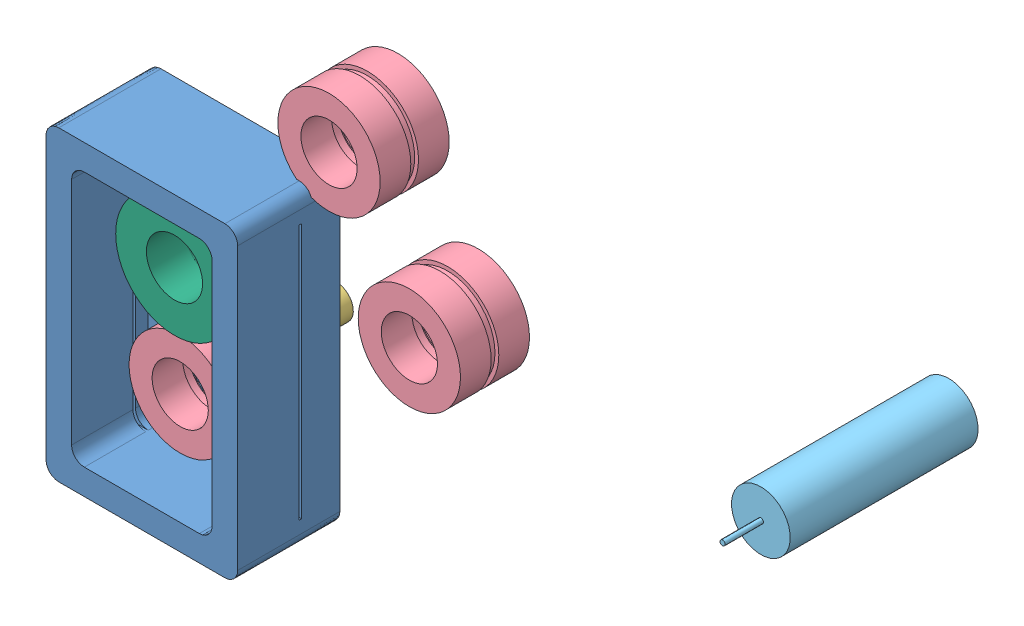
SolidWorks assembly MotorHolderAssembly, configuration Default. Lengths in mm.
Overall size (54.59 39.49 38.35).
8 component instances, 6 part files, 7 mates.
Components (placement in the parent):
- Holder-1: Holder [Default] at (-12.0978 19.1611 -15.3648) size (19.05 30.48 10.16)
- BallbearingPinchRollInterface-1: BallbearingPinchRollInterface [Default] at (-10.3379 24.5042 -15.3648) x (-0.976423 -0.215867 0) z (0 0 -1) size (3.3 3.3 8.38)
- MotorPinchRollInterface-1: MotorPinchRollInterface [Default] at (-9.8767 12.9721 -15.3648) x (-0.80394 -0.59471 0) z (0 0 -1) size (3.3 3.3 9.53)
- WheelTreads5-1: WheelTreads5 [Default] at (-9.5578 13.0937 -12.8248) size (10.16 10.16 6.86)
- WheelTreads5-2: WheelTreads5 [Default] at (16.4064 31.6632 -9.6374) size (10.16 10.16 6.86)
- quickmotormodel-1: quickmotormodel [Default] at (32.2814 15.1772 -43.5588) x (0.993945 0.109881 0) z (0 0 1) size (5.84 5.84 22.48)
- WheelTreads3-1: WheelTreads3 [Default] at (-9.5578 24.2697 -12.2601) size (11.68 11.68 6.86)
- WheelTreads5-3: WheelTreads5 [Default] at (1.6555 37.7244 -16.4051) size (10.16 10.16 6.86)
Mates (geometry in assembly coordinates):
- Coincident1: coincident anti-aligned: plane of Holder-1 through (-12.0978 19.1611 -15.3648) normal (0 0 -1); plane of MotorPinchRollInterface-1 through (-9.8767 12.9721 -15.3648) normal (0 0 1)
- Coincident2: coincident aligned: plane of Holder-1 through (-12.0978 19.1611 -15.3648) normal (0 0 -1); circle of BallbearingPinchRollInterface-1
- Coincident3: coincident anti-aligned: plane of MotorPinchRollInterface-1 through (-9.8767 12.9721 -24.8898) normal (0 0 -1); plane of quickmotormodel-1 through (32.2814 15.1772 -24.8898) normal (0 0 1)
- Coincident4: coincident: circle of Holder-1; circle of WheelTreads5-1
- Coincident5: coincident anti-aligned: plane of quickmotormodel-1 through (32.2814 15.1772 -24.8898) normal (0 0 1); plane of MotorPinchRollInterface-1 through (-9.8767 12.9721 -24.8898) normal (0 0 -1)
- Parallel3: parallel anti-aligned: plane of MotorPinchRollInterface-1 through (-9.8767 12.9721 -22.3498) normal (0 0 -1); plane of quickmotormodel-1 through (32.2814 15.1772 -21.0798) normal (0 0 1)
- Tangent2: tangent: circle of MotorPinchRollInterface-1; plane of quickmotormodel-1 through (32.2814 15.1772 -24.8898) normal (0 0 1)
